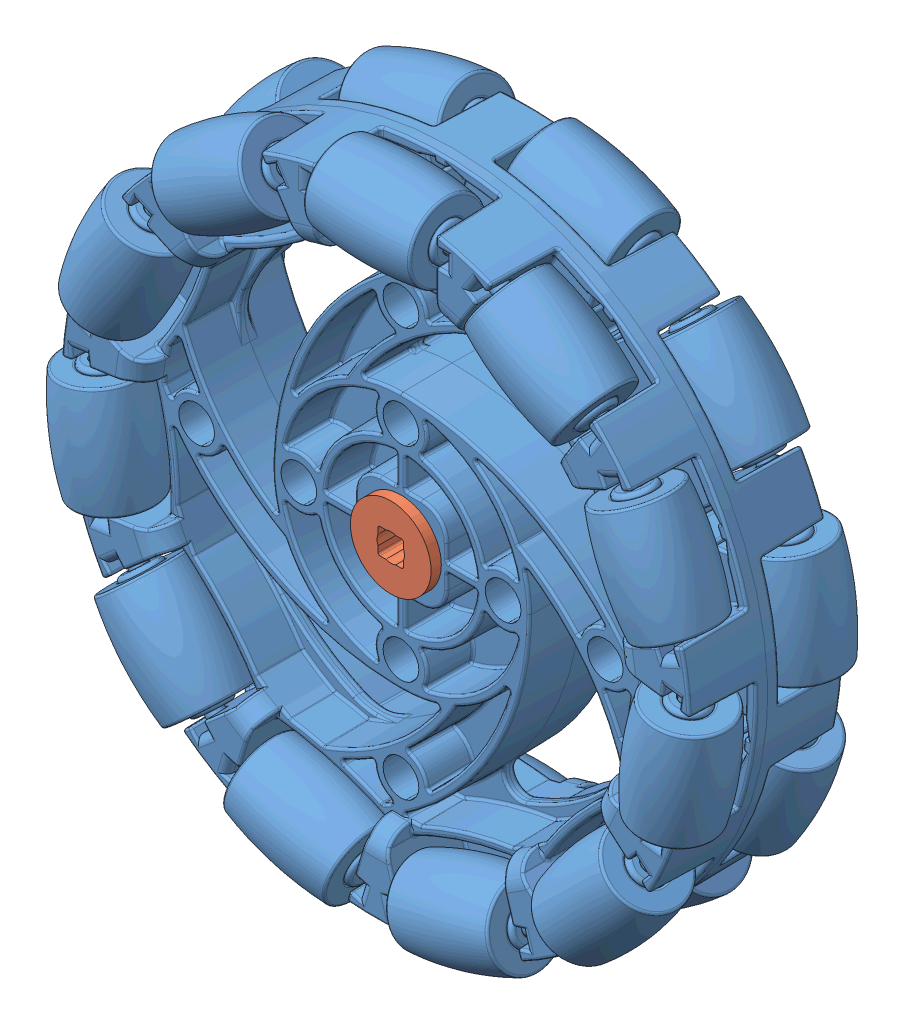
SolidWorks assembly 3.25 Omni Wheel w metal inserts, configuration Default. Lengths in mm.
Overall size (85.9 85.86 35.67).
3 component instances, 2 part files, 5 mates.
Components (placement in the parent):
- 3.25in Omni Directional Wheel-1: 3.25in Omni Directional Wheel [Default] at (-26.447 -27.0837 32.8116) size (85.9 85.86 35.67)
- Gear HS Insert Metal-1: Gear HS Insert Metal [Default] at (-26.447 -27.0837 40.4316) x (1 0 0) z (0 1 0) size (10.03 5.08 10.03)
- Gear HS Insert Metal-2: Gear HS Insert Metal [Default] at (-26.447 -27.0837 25.1916) x (0.003572 -0.999994 0) z (-0.999994 -0.003572 0) size (10.03 5.08 10.03)
Mates (geometry in assembly coordinates):
- Concentric1: concentric: cylinder of 3.25in Omni Directional Wheel-1 through (-26.447 -27.0837 -60.1524) axis (0 0 1) radius 3.425; cylinder of Gear HS Insert Metal-1 through (-26.447 -27.0837 86.4056) axis (0 0 -1) radius 1.7018
- Coincident1: coincident: plane of 3.25in Omni Directional Wheel-1 through (-26.447 -27.0837 39.1616) normal (0 0 1); plane of Gear HS Insert Metal-1 through (-21.4305 -27.0837 39.1616) normal (0 0 -1)
- Coincident2: coincident: plane of 3.25in Omni Directional Wheel-1 through (-26.447 -27.0837 26.4616) normal (0 0 -1); plane of Gear HS Insert Metal-2 through (-26.43 -32.0786 31.5416) normal (0 0 1)
- Concentric3: concentric: cylinder of 3.25in Omni Directional Wheel-1 through (-26.447 -27.0837 -60.1524) axis (0 0 1) radius 3.425; cylinder of Gear HS Insert Metal-2 through (-26.4479 -27.0621 -15.7024) axis (0 0 1) radius 1.7018
- Concentric4: concentric: cylinder of Gear HS Insert Metal-1 through (-26.447 -27.0837 86.4056) axis (0 0 -1) radius 1.7018; cylinder of Gear HS Insert Metal-2 through (-26.447 -27.0837 -20.7824) axis (0 0 1) radius 1.7018
